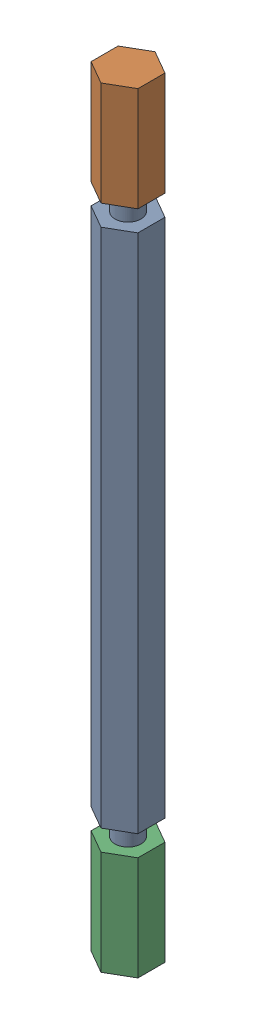
SolidWorks assembly 支撑装配, configuration 默认. Lengths in mm.
Overall size (6.75 74 6.5).
3 component instances, 2 part files, 6 mates.
Components (placement in the parent):
- 支撑螺柱-1: 支撑螺柱 [默认] at (-23.3918 -7.2815 0) size (4.5 62 5.2)
- 支撑螺帽-1: 支撑螺帽 [默认] at (-23.3918 24.7185 0) x (-0.5 0 -0.866025) z (-0.866025 0 0.5) size (4.5 10 5.2)
- 支撑螺帽-2: 支撑螺帽 [默认] at (-23.3918 -39.2815 0) x (0.5 0 -0.866025) z (0.866025 0 0.5) size (4.5 10 5.2)
Mates (geometry in assembly coordinates):
- 同心1: concentric aligned: cylinder of 支撑螺柱-1 through (-23.3918 23.7185 0) axis (0 -1 0) radius 1.25; cylinder of 支撑螺帽-1 through (-23.3918 25.7185 0) axis (0 -1 0) radius 1.25
- 同心2: concentric anti-aligned: cylinder of 支撑螺柱-1 through (-23.3918 23.7185 0) axis (0 -1 0) radius 1.25; cylinder of 支撑螺帽-2 through (-23.3918 -40.2815 0) axis (0 1 0) radius 1.25
- 距离1: distance = 2 mm anti-aligned: plane of 支撑螺帽-1 through (-23.3918 19.7185 0) normal (0 -1 0); plane of 支撑螺柱-1 through (-23.3918 17.7185 0) normal (0 1 0)
- 平行1: parallel anti-aligned: line of 支撑螺柱-1 through (-23.3918 17.7185 2.5981) axis (0.866025 0 -0.5); line of 支撑螺帽-1 through (-21.1418 20.7185 1.299) axis (-0.866025 0 0.5)
- 平行2: parallel aligned: line of 支撑螺柱-1 through (-23.3918 -32.2815 2.5981) axis (0.866025 0 -0.5); line of 支撑螺帽-2 through (-23.3918 -35.2815 2.5981) axis (0.866025 0 -0.5)
- 宽度1: width anti-aligned: plane of 支撑螺柱-1 through (-23.3918 17.7185 0) normal (0 1 0); plane of 支撑螺帽-2 through (-23.3918 -32.2815 0) normal (0 -1 0); plane of 支撑螺柱-1 through (-23.3918 -45.2815 0) normal (0 -1 0); plane of 支撑螺帽-1 through (-23.3918 30.7185 0) normal (0 1 0)
